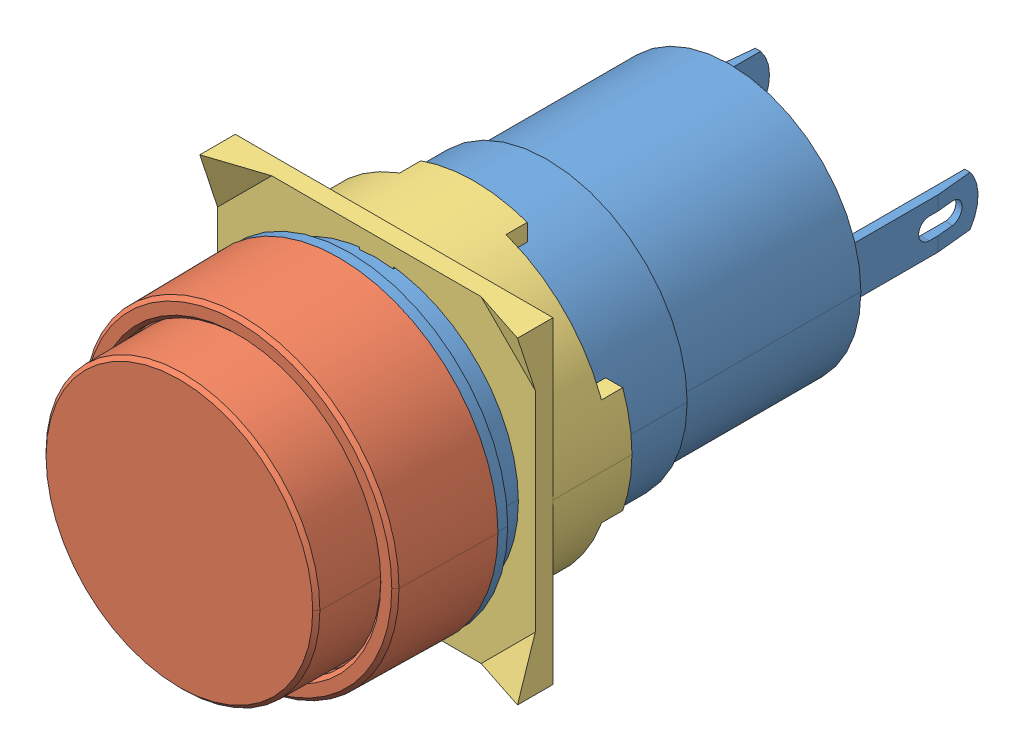
SolidWorks assembly cad_STEP_OUTSIDE-AL6M-P.STEP, configuration 預設. Lengths in mm.
Overall size (17.9 17.9 39.2).
3 component instances, 3 part files, 0 mates.
Components (placement in the parent):
- A6-P-Body.STEP-1: A6-P-Body.STEP [預設] at origin size (17.8 17.8 30.2)
- A6-Operator-Round.STEP-1: A6-Operator-Round.STEP [預設] at origin size (17.9 17.9 9)
- 16-NUT-SET.STEP-1: 16-NUT-SET.STEP [預設] at (0 0 -5.8) size (17.9 17.9 6.5)
